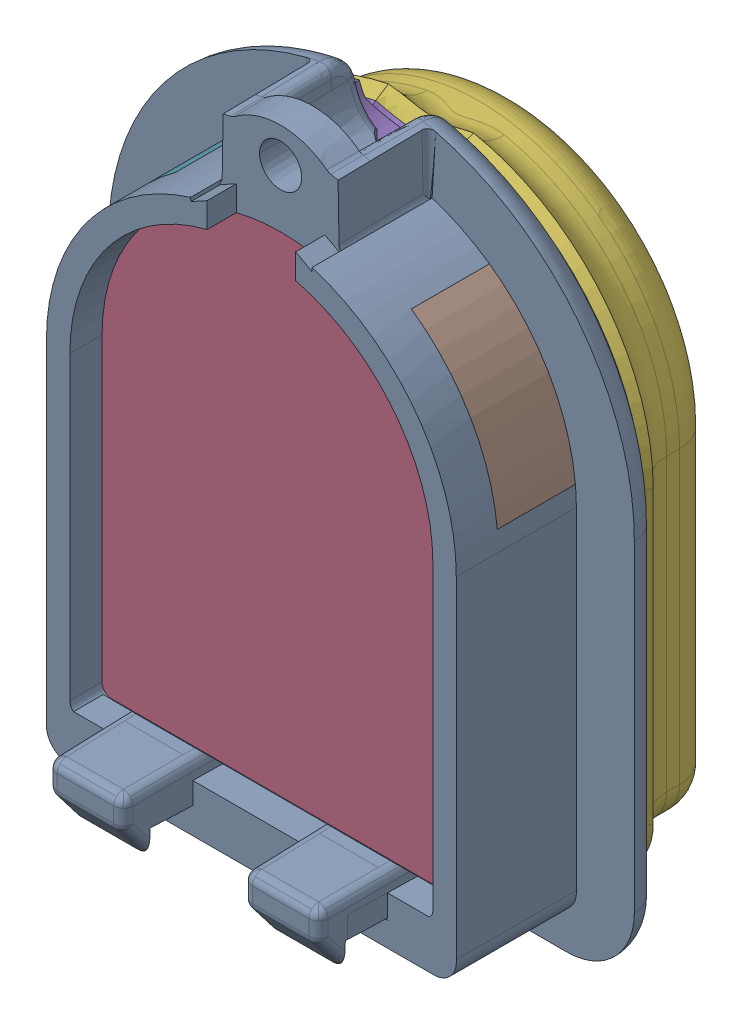
SolidWorks assembly Original, configuration 默认. Lengths in mm.
Overall size (26.95 34.26 17.16).
7 component instances, 6 part files, 18 mates.
Components (placement in the parent):
- Tip1-1: Tip1 [默认] at (-1.9035 7.7463 -5.5591) size (26.95 34.26 11.2)
- lensnew-1: lensnew [默认] at (-1.9035 7.7463 -5.5591) size (18.6 25.2 6)
- Skin0.2-1: Skin0.2 [默认] at (-1.9035 7.4963 -5.5591) x (-1 0 0) z (0 0 -1) size (23.9 30.06 5.2)
- Skin1-1: Skin1 [默认] at (-1.9035 7.4963 -5.5591) x (-1 0 0) z (0 0 -1) size (22.77 29.32 5.25)
- sidelens1-1: sidelens1 [默认] at (-1.9035 7.7463 -6.2091) size (6.4 7.71 4)
- sidelens1-2: sidelens1 [默认] at (-1.9035 7.7463 2.0909) x (-1 0 0) z (0 0 -1) size (6.4 7.71 4)
- bottomlens-1: bottomlens [默认] at (-5.9035 -10.5037 0.4409) x (1 0 0) z (0 1 0) size (8 4.5 2.35)
Mates (geometry in assembly coordinates):
- 同心1: concentric aligned: cylinder of Tip1-1 through (-1.9035 7.7463 51.2878) axis (0 0 -1) radius 9.3; cylinder of lensnew-1 through (-1.9035 7.7463 0.4409) axis (0 0 -1) radius 9.3
- 重合1: coincident anti-aligned: plane of Tip1-1 through (-1.9035 -8.1537 51.2878) normal (0 1 0); plane of lensnew-1 through (-11.2035 -8.1537 0.4409) normal (0 -1 0)
- 重合2: coincident aligned: plane of Tip1-1 through (-1.964 4.3089 -5.5591) normal (0 0 -1); plane of lensnew-1 through (-1.9035 7.7463 -5.5591) normal (0 0 -1)
- 重合3: coincident anti-aligned: plane of lensnew-1 through (-1.9035 7.7463 -5.5591) normal (0 0 -1); plane of Skin0.2-1 through (-1.9035 7.4963 -5.5591) normal (0 0 1)
- 同心2: concentric aligned: cone of Tip1-1 through (-1.9035 19.9963 -1.0591) axis (0 0 1); cylinder of Skin0.2-1 through (-1.9035 19.9963 -6.3091) axis (0 0 1) radius 2.75
- 宽度1: width aligned: plane of Skin0.2-1 through (-13.8535 7.4963 -5.5591) normal (-1 0 0); plane of Skin0.2-1 through (10.0465 7.4963 -5.5591) normal (1 0 0); plane of Tip1-1 through (-12.4035 7.7463 2.0909) normal (-1 0 0); plane of Tip1-1 through (8.5965 7.7463 2.0909) normal (1 0 0)
- 重合4: coincident anti-aligned: plane of Skin0.2-1 through (-1.9035 7.4963 -10.7591) normal (0 0 -1); plane of Skin1-1 through (-1.9035 7.4963 -10.7591) normal (0 0 1)
- 宽度2: width anti-aligned: plane of Skin0.2-1 through (-13.8535 7.4963 -5.5591) normal (-1 0 0); plane of Skin0.2-1 through (10.0465 7.4963 -5.5591) normal (1 0 0); plane of Skin1-1 through (-12.8325 0.0508 -6.2245) normal (-0.891007 0 0.45399); plane of Skin1-1 through (9.0255 0.0508 -6.2245) normal (0.891007 0 0.45399)
- 重合5: coincident aligned: cone of Skin0.2-1 through (-1.9035 7.4963 -6.2245) axis (0 0 1); cone of Skin1-1 through (-1.9035 7.4963 -6.2245) axis (0 0 1)
- 重合6: coincident anti-aligned: plane of Tip1-1 through (-16.7251 9.2061 -4.0591) normal (0.104528 0.994522 0); plane of sidelens1-1 through (8.4147 6.5638 -0.0591) normal (-0.104528 -0.994522 0)
- 重合7: coincident anti-aligned: plane of Tip1-1 through (-1.9035 7.7463 -4.0591) normal (0 0 1); plane of sidelens1-1 through (8.4147 6.5638 -4.0591) normal (0 0 -1)
- 同心3: concentric aligned: cylinder of Tip1-1 through (-1.9035 7.7463 2.0909) axis (0 0 -1) radius 10.5; cylinder of sidelens1-1 through (-1.9035 7.7463 -0.0591) axis (0 0 -1) radius 10.5
- 同心4: concentric anti-aligned: cylinder of Tip1-1 through (-1.9035 7.7463 2.0909) axis (0 0 -1) radius 10.5; cylinder of sidelens1-2 through (-1.9035 7.7463 -4.0591) axis (0 0 1) radius 10.5
- 重合8: coincident anti-aligned: plane of Tip1-1 through (12.0819 17.1622 -0.0591) normal (0.104528 -0.994522 0); plane of sidelens1-2 through (-13.0579 14.5199 -4.0591) normal (-0.104528 0.994522 0)
- 重合9: coincident anti-aligned: plane of Tip1-1 through (-1.9035 7.7463 -4.0591) normal (0 0 1); plane of sidelens1-2 through (-1.9035 7.7463 -4.0591) normal (0 0 -1)
- 重合10: coincident anti-aligned: plane of lensnew-1 through (-11.2035 -8.1537 0.4409) normal (0 -1 0); plane of bottomlens-1 through (-5.9035 -8.1537 0.4409) normal (0 1 0)
- 重合11: coincident anti-aligned: plane of Tip1-1 through (-5.9035 -18.1537 0.4409) normal (0 0 -1); plane of bottomlens-1 through (-5.9035 -8.1537 0.4409) normal (0 0 1)
- 重合12: coincident anti-aligned: plane of Tip1-1 through (2.0965 -18.1537 0.4409) normal (-1 0 0); plane of bottomlens-1 through (2.0965 -8.1537 0.4409) normal (1 0 0)
